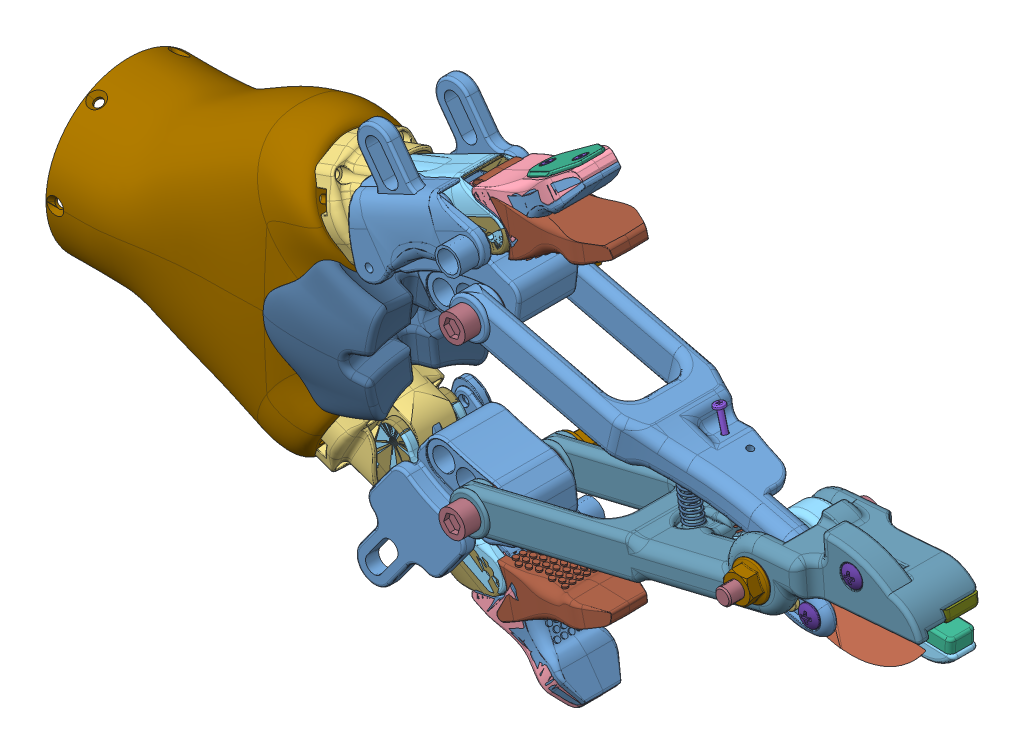
SolidWorks assembly Assiem_Gripper_Utensile, configuration Default. Lengths in mm.
Overall size (320.66 194.91 65.01).
98 component instances, 35 part files, 61 mates.
Components (placement in the parent):
- Assieme_Case_sx-1: Assieme_Case_sx [Default] at origin size (167.73 210 74) (hidden)
  - Case_sx_v5-1: Case_sx_v5 [Default] at origin size (167.73 210 74)
  - Grano_filettato_ENT3_6-1: Grano_filettato_ENT3_6 [Default] at (62 96 31) size (5 5 6)
  - Grano_filettato_ENT3_6-20: Grano_filettato_ENT3_6 [Default] at (109.2647 71.1343 31) x (0.987351 0.158553 0) z (0 0 1) size (5 5 6)
  - Grano_filettato_ENT3_6-22: Grano_filettato_ENT3_6 [Default] at (127 35 31) x (0.959125 0.282984 0) z (0 0 1) size (5 5 6)
  - Grano_filettato_ENT3_6-24: Grano_filettato_ENT3_6 [Default] at (127 -35 31) x (0.928571 0.371154 0) z (0 0 1) size (5 5 6)
  - Grano_filettato_ENT3_6-26: Grano_filettato_ENT3_6 [Default] at (109.2647 -71.1343 31) x (0.906989 0.421154 0) z (0 0 1) size (5 5 6)
  - Grano_filettato_ENT3_6-28: Grano_filettato_ENT3_6 [Default] at (62 -96 31) x (0.902849 0.429957 0) z (0 0 1) size (5 5 6)
  - Grano_filettato_ENT3_6-30: Grano_filettato_ENT3_6 [Default] at (6 8 31) x (0.823258 0.567667 0) z (0 0 1) size (5 5 6)
  - Grano_filettato_ENT3_6-32: Grano_filettato_ENT3_6 [Default] at (6 -8 31) x (0.744275 0.667874 0) z (0 0 1) size (5 5 6)
  - Grano_filettato_ENT3_6-34: Grano_filettato_ENT3_6 [Default] at (14 4 0) x (0 0.852489 -0.522745) z (1 0 0) size (5 5 6)
  - Grano_filettato_ENT3_6-36: Grano_filettato_ENT3_6 [Default] at (14 -4 0) x (0 0.932569 -0.360992) z (1 0 0) size (5 5 6)
  - Grano_MSTH6_20-1: Grano_MSTH6_20 [Default] at (0 30.95 -26.5) x (0 0 -1) z (-1 0 0) size (20 6 5.85)
  - Grano_MSTH6_20-2: Grano_MSTH6_20 [Default] at (0 -30.95 -26.5) x (0 0 -1) z (-1 0 0) size (20 6 5.85)
- Assieme_Ingresso_sup-1: Assieme_Ingresso_sup [Default] at (0 30.95 -16.0586) x (0.999806 -0.019711 0) z (0 0 1) size (56.76 55.15 35.08)
  - Ingresso_sup_f_v2-1: Ingresso_sup_f_v2 [Default] at origin size (77.62 68.68 45)
  - BOCCOLA_RSONLINE-1: BOCCOLA_RSONLINE [Default] at (37.0002 1.9973 4.0586) x (0 0 1) z (-0.862361 0.506294 0) size (4 12 12)
  - BOCCOLA_RSONLINE-2: BOCCOLA_RSONLINE [Default] at (37.0002 1.9973 28.0586) x (0 0 -1) z (0.381483 -0.924376 0) size (4 12 12)
- Assieme_case_dx-1: Assieme_case_dx [Default] at (0 0 34) size (145 210 23.5) (hidden)
  - Case_dx_v5-1: Case_dx_v5 [Default] at origin size (145 210 16)
  - Grano_MSTH6_20-1: Grano_MSTH6_20 [Default] at (0 30.95 -7.5) x (0 0 1) z (-1 0 0) size (20 6 5.85)
  - Grano_MSTH6_20-2: Grano_MSTH6_20 [Default] at (0 -30.95 -7.5) x (0 0 1) z (-1 0 0) size (20 6 5.85)
- KG-2-1: KG-2 [Default] at (-119.5648 0 0) x (-1 0 0) z (0 -1 0) size (190.12 63.02 189.85)
  - KG-2.STEP-1: KG-2.STEP [Default] at origin size (198.06 63.02 194.91)
    - AM 3540 0001 - Linear Actuator - 35mm - 40N - Dummy simple.STEP-1: AM 3540 0001 - Linear Actuator - 35mm - 40N - Dummy simple.STEP [Default] at (-86.7275 0 30.1692) x (-0.939693 0 0.34202) z (0 1 0) size (59.16 39 39) (hidden)
      - DummyActuator_D_faut.STEP-1: DummyActuator_D_faut.STEP [Default] at origin size (44.13 37 37)
      - MF3915 0001 - Mico finger actuator plastic cup for junction with hand_D_faut.STEP-1: MF3915 0001 - Mico finger actuator plastic cup for junction with hand_D_faut.STEP [Default] at (-13 0 0) x (-1 0 0) z (0 0 -1) size (15.02 39 39)
    - AM 3540 0001 - Linear Actuator - 35mm - 40N - Dummy simple.STEP-2: AM 3540 0001 - Linear Actuator - 35mm - 40N - Dummy simple.STEP [Default] at (-86.7275 0 -30.1692) x (-0.939693 0 -0.34202) z (0 -1 0) size (59.16 39 39) (hidden)
      - DummyActuator_D_faut.STEP-1: DummyActuator_D_faut.STEP [Default] at origin size (44.13 37 37)
      - MF3915 0001 - Mico finger actuator plastic cup for junction with hand_D_faut.STEP-1: MF3915 0001 - Mico finger actuator plastic cup for junction with hand_D_faut.STEP [Default] at (-13 0 0) x (-1 0 0) z (0 0 -1) size (15.02 39 39)
    - AM 3240 0004 - Plastic Finger Assembly Mico - 32mm - 2 Phalanges_simple_D_faut.STEP-1: AM 3240 0004 - Plastic Finger Assembly Mico - 32mm - 2 Phalanges_simple_D_faut.STEP [Default] at (-93.8204 0 -32.7508) x (-0.34202 0 0.939693) z (0.939693 0 0.34202) size (47.27 36.79 116.14)
      - MI 0000 0001 - 1.0.0.0011_simple_D_faut.STEP-1: MI 0000 0001 - 1.0.0.0011_simple_D_faut.STEP [Default] at (0 0 -13.5762) x (0 0 1) z (0 1 0) size (36.76 36.64 36.79)
      - MI 0000 0002 - 1.0.0.0005_simple_molded_version.STEP-1: MI 0000 0002 - 1.0.0.0005_simple_molded_version.STEP [Default] at (-0.0949 0 -66.3867) x (-0.34202 0 -0.939693) z (0 -1 0) size (53.08 21.63 24.15)
      - MI 0000 0004 - 1.0.0.0005_simple_D_faut.STEP-1: MI 0000 0004 - 1.0.0.0005_simple_D_faut.STEP [Default] at (5.2287 0 -24.6775) x (-0.173648 0 -0.984808) z (0 -1 0) size (57.72 28.12 23.54)
      - MI 1502 0001 - 1.0.0.0002_simple_D_faut.STEP-1: MI 1502 0001 - 1.0.0.0002_simple_D_faut.STEP [Default] at (-16.391 0 -80.0717) x (0 1 0) z (-0.97437 0 0.224951) size (19.37 25 1.26)
      - MH 0205 0003 - M2x5 washer, stainless, black oxyde, 0.3 thick_simple_D_faut.STEP-1: MH 0205 0003 - M2x5 washer, stainless, black oxyde, 0.3 thick_simple_D_faut.STEP [Default] at (-18.5389 0 -84.7073) x (-0.224951 0.000713 -0.97437) z (0.97437 0 -0.224951) size (5 5 0.3)
      - MH 0205 0003 - M2x5 washer, stainless, black oxyde, 0.3 thick_simple_D_faut.STEP-2: MH 0205 0003 - M2x5 washer, stainless, black oxyde, 0.3 thick_simple_D_faut.STEP [Default] at (-21.9132 0 -99.3229) x (-0.224951 0.000713 -0.97437) z (0.97437 0 -0.224951) size (5 5 0.3)
      - MH 0204 0004 - Lamix M2x4 stainless steel screw, head 0.3 thick,  black colored_simple_D_faut.STEP-1: MH 0204 0004 - Lamix M2x4 stainless steel screw, head 0.3 thick,  black colored_simple_D_faut.STEP [Default] at (-14.6414 0 -85.6071) x (-0.028802 0.991769 -0.124755) z (0.2231 0.128036 0.96635) size (4 4.3 4)
      - MH 0204 0004 - Lamix M2x4 stainless steel screw, head 0.3 thick,  black colored_simple_D_faut.STEP-2: MH 0204 0004 - Lamix M2x4 stainless steel screw, head 0.3 thick,  black colored_simple_D_faut.STEP [Default] at (-18.0157 0 -100.2227) x (0.215322 0.289446 0.932661) z (0.065111 -0.957194 0.282028) size (4 4.3 4)
      - MH 0204 0004 - Lamix M2x4 stainless steel screw, head 0.3 thick,  black colored_simple_D_faut.STEP-3: MH 0204 0004 - Lamix M2x4 stainless steel screw, head 0.3 thick,  black colored_simple_D_faut.STEP [Default] at (-0.0949 -7.35 -66.3867) x (-0.96685 0 -0.255343) z (-0.255343 0 0.96685) size (4 4.3 4) (hidden)
      - MH 0204 0004 - Lamix M2x4 stainless steel screw, head 0.3 thick,  black colored_simple_D_faut.STEP-4: MH 0204 0004 - Lamix M2x4 stainless steel screw, head 0.3 thick,  black colored_simple_D_faut.STEP [Default] at (10.5 -7.35 -23.5762) x (-0.96685 0 -0.255343) z (-0.255343 0 0.96685) size (4 4.3 4) (hidden)
      - MH 0204 0004 - Lamix M2x4 stainless steel screw, head 0.3 thick,  black colored_simple_D_faut.STEP-5: MH 0204 0004 - Lamix M2x4 stainless steel screw, head 0.3 thick,  black colored_simple_D_faut.STEP [Default] at (-0.0949 7.35 -66.3867) size (4 4.3 4) (hidden)
      - MH 0204 0004 - Lamix M2x4 stainless steel screw, head 0.3 thick,  black colored_simple_D_faut.STEP-6: MH 0204 0004 - Lamix M2x4 stainless steel screw, head 0.3 thick,  black colored_simple_D_faut.STEP [Default] at (10.5 7.35 -23.5762) size (4 4.3 4) (hidden)
    - AM 3240 0004 - Plastic Finger Assembly Mico - 32mm - 2 Phalanges_simple_D_faut.STEP-2: AM 3240 0004 - Plastic Finger Assembly Mico - 32mm - 2 Phalanges_simple_D_faut.STEP [Default] at (-93.8204 0 32.7508) x (-0.34202 0 -0.939693) z (0.939693 0 -0.34202) size (47.27 36.79 116.14)
      - MI 0000 0001 - 1.0.0.0011_simple_D_faut.STEP-1: MI 0000 0001 - 1.0.0.0011_simple_D_faut.STEP [Default] at (0 0 -13.5762) x (0 0 1) z (0 1 0) size (36.76 36.64 36.79)
      - MI 0000 0002 - 1.0.0.0005_simple_molded_version.STEP-1: MI 0000 0002 - 1.0.0.0005_simple_molded_version.STEP [Default] at (-0.0949 0 -66.3867) x (-0.34202 0 -0.939693) z (0 -1 0) size (53.08 21.63 24.15)
      - MI 0000 0004 - 1.0.0.0005_simple_D_faut.STEP-1: MI 0000 0004 - 1.0.0.0005_simple_D_faut.STEP [Default] at (5.2287 0 -24.6775) x (-0.173648 0 -0.984808) z (0 -1 0) size (57.72 28.12 23.54)
      - MI 1502 0001 - 1.0.0.0002_simple_D_faut.STEP-1: MI 1502 0001 - 1.0.0.0002_simple_D_faut.STEP [Default] at (-16.391 0 -80.0717) x (0 1 0) z (-0.97437 0 0.224951) size (19.37 25 1.26)
      - MH 0205 0003 - M2x5 washer, stainless, black oxyde, 0.3 thick_simple_D_faut.STEP-1: MH 0205 0003 - M2x5 washer, stainless, black oxyde, 0.3 thick_simple_D_faut.STEP [Default] at (-18.5389 0 -84.7073) x (-0.224951 0.000713 -0.97437) z (0.97437 0 -0.224951) size (5 5 0.3)
      - MH 0205 0003 - M2x5 washer, stainless, black oxyde, 0.3 thick_simple_D_faut.STEP-2: MH 0205 0003 - M2x5 washer, stainless, black oxyde, 0.3 thick_simple_D_faut.STEP [Default] at (-21.9132 0 -99.3229) x (-0.224951 0.000713 -0.97437) z (0.97437 0 -0.224951) size (5 5 0.3)
      - MH 0204 0004 - Lamix M2x4 stainless steel screw, head 0.3 thick,  black colored_simple_D_faut.STEP-1: MH 0204 0004 - Lamix M2x4 stainless steel screw, head 0.3 thick,  black colored_simple_D_faut.STEP [Default] at (-14.6414 0 -85.6071) x (-0.028802 0.991769 -0.124755) z (0.2231 0.128036 0.96635) size (4 4.3 4)
      - MH 0204 0004 - Lamix M2x4 stainless steel screw, head 0.3 thick,  black colored_simple_D_faut.STEP-2: MH 0204 0004 - Lamix M2x4 stainless steel screw, head 0.3 thick,  black colored_simple_D_faut.STEP [Default] at (-18.0157 0 -100.2227) x (0.215322 0.289446 0.932661) z (0.065111 -0.957194 0.282028) size (4 4.3 4)
      - MH 0204 0004 - Lamix M2x4 stainless steel screw, head 0.3 thick,  black colored_simple_D_faut.STEP-3: MH 0204 0004 - Lamix M2x4 stainless steel screw, head 0.3 thick,  black colored_simple_D_faut.STEP [Default] at (-0.0949 -7.35 -66.3867) x (-0.96685 0 -0.255343) z (-0.255343 0 0.96685) size (4 4.3 4) (hidden)
      - MH 0204 0004 - Lamix M2x4 stainless steel screw, head 0.3 thick,  black colored_simple_D_faut.STEP-4: MH 0204 0004 - Lamix M2x4 stainless steel screw, head 0.3 thick,  black colored_simple_D_faut.STEP [Default] at (10.5 -7.35 -23.5762) x (-0.96685 0 -0.255343) z (-0.255343 0 0.96685) size (4 4.3 4) (hidden)
      - MH 0204 0004 - Lamix M2x4 stainless steel screw, head 0.3 thick,  black colored_simple_D_faut.STEP-5: MH 0204 0004 - Lamix M2x4 stainless steel screw, head 0.3 thick,  black colored_simple_D_faut.STEP [Default] at (-0.0949 7.35 -66.3867) size (4 4.3 4) (hidden)
      - MH 0204 0004 - Lamix M2x4 stainless steel screw, head 0.3 thick,  black colored_simple_D_faut.STEP-6: MH 0204 0004 - Lamix M2x4 stainless steel screw, head 0.3 thick,  black colored_simple_D_faut.STEP [Default] at (10.5 7.35 -23.5762) size (4 4.3 4) (hidden)
    - MT0062 0002 - Hand Shell Mico_D_faut.STEP-1: MT0062 0002 - Hand Shell Mico_D_faut.STEP [Default] at origin size (108.05 63.02 113.68)
    - MO 0000 0009 - rubber part handfront_D_faut.STEP-1: MO 0000 0009 - rubber part handfront_D_faut.STEP [Default] at (-21.4262 -5.1521 0) size (50.65 54.11 65.34)
- Assieme_Ingresso_sup-2: Assieme_Ingresso_sup [Default] at (0 -30.95 16.0586) x (0.999806 0.019711 0) z (0 0 -1) size (56.76 55.15 35.08)
  - Ingresso_sup_f_v2-1: Ingresso_sup_f_v2 [Default] at origin size (77.62 68.68 45)
  - BOCCOLA_RSONLINE-1: BOCCOLA_RSONLINE [Default] at (37.0002 1.9973 4.0586) x (0 0 1) z (-0.862361 0.506294 0) size (4 12 12)
  - BOCCOLA_RSONLINE-2: BOCCOLA_RSONLINE [Default] at (37.0002 1.9973 28.0586) x (0 0 -1) z (0.381483 -0.924376 0) size (4 12 12)
- FALANGETTA-1: FALANGETTA [Default] at (37.0133 54.9289 0) x (0.9838 0.179268 0) z (0 0 -1) size (53.08 21.63 24.15)
- Falange-1: Falange [Default] at (-0.6773 36.2898 0) x (0.874281 0.48542 0) z (0 0 -1) size (57.72 28.12 23.54)
- Albero_scanal_6mm-2: Albero_scanal_6mm [Default] at (144.9873 0 30.2) x (-0.467784 -0.883843 0) z (0 0 1) size (10 10 56)
- Assieme_TELAIO_COMPR-TRAZ-1: Assieme_TELAIO_COMPR-TRAZ [Default] at (-27.313 16.6114 -30.194) x (0.996829 0.079574 0) z (0 0 1) size (175.42 51.93 39.5)
  - TELAIO_COMPR-TRAZ-1: TELAIO_COMPR-TRAZ [Default] at (170.4321 -30.2694 11.694) size (175.42 51.93 39.5)
  - BATTENTE-1: BATTENTE [Default] at (278.1489 -5.0569 35.794) x (1 0 0) z (0 0 -1) size (29.64 18.26 6.08)
  - materiale_SOFT2-1: materiale_SOFT2 [Default] at (178.4321 -31.2694 31.694) x (-1 0 0) z (0 0 -1) size (38 5 13)
  - BOCCOLA_RSONLINE-1: BOCCOLA_RSONLINE [Default] at (170.4321 -30.2694 11.194) x (0 0 1) z (0.389783 0.920907 0) size (4 12 12)
  - BOCCOLA_RSONLINE-2: BOCCOLA_RSONLINE [Default] at (170.4321 -30.2694 49.694) x (0 0 -1) z (0.983445 0.181207 0) size (4 12 12)
  - pan head cross recess screw-2: pan head cross recess screw [ISO 7045 - M4 x 8 - Z - 8N] at (203.0321 -18.9694 44.794) x (0 0 -1) z (0.991033 0.133621 0) size (11.02 8 8)
  - hex thin nut chamfered gradeab_isEDEEEEo-1: hex thin nut chamfered gradeab_isEDEEEEo [ISO - 4035 - M4 - N] at (203.0321 -18.9694 34.794) x (0.5 -0.866025 0) z (0 0 1) size (7 8.08 2.2)
- Assieme_PORTALAMA_COMPR-TRAZ-1: Assieme_PORTALAMA_COMPR-TRAZ [Default] at (112.7156 34.929 -45.3573) x (0.996829 -0.079574 0) z (0 0 1) size (170.01 48.69 40)
  - PORTALAMA specchiato_COMPR-TRAZ-1: PORTALAMA specchiato_COMPR-TRAZ [Default] at (34.9488 -32.2503 55.8573) size (138.08 48.69 40)
  - LAMA5 NUOVA-1: LAMA5 NUOVA [Default] at (48.0839 -41.5236 50.8573) x (0.999898 0.014284 0) z (0 0 1) size (52.01 17.5 2.12)
  - hex thin nut chamfered gradeab_isEDEEEEo-4: hex thin nut chamfered gradeab_isEDEEEEo [ISO - 4035 - M4 - N] at (48.0839 -41.5236 49.8573) x (0.999492 -0.031877 0) z (0 0 1) size (7 8.08 2.2)
  - BOCCOLA_RSONLINE-1: BOCCOLA_RSONLINE [Default] at (34.9488 -32.2503 56.3573) x (0 0 -1) z (-0.166528 -0.986037 0) size (4 12 12)
  - BOCCOLA_RSONLINE-2: BOCCOLA_RSONLINE [Default] at (34.9488 -32.2503 45.3573) x (0 0 1) z (0.391952 0.919986 0) size (4 12 12)
  - hex thin nut chamfered gradeab_isEDEEEEo-7: hex thin nut chamfered gradeab_isEDEEEEo [ISO - 4035 - M2 - N] at (-0.2058 -19.6931 40.3573) x (0.943396 0.331667 0) z (-0.331667 0.943396 0) size (4 4.62 1.2)
  - pan head cross recess screw-4: pan head cross recess screw [ISO 7045 - M4 x 8 - Z - 8N] at (48.0839 -41.5232 57.1573) x (0 0 -1) z (0.974254 0.225454 0) size (11.02 8 8)
  - pan head cross recess screw_iso-1: pan head cross recess screw_iso [ISO 7045 - M3 x 10 - Z - 10N] at (40.0839 -41.6379 56.4573) x (0 0 -1) z (0.99999 0.004568 0) size (9.35 5.6 5.6)
  - hex thin nut chamfered gradeab_iso-1: hex thin nut chamfered gradeab_iso [ISO - 4035 - M3 - N] at (40.0839 -41.6379 49.8573) x (0.820804 0.571211 0) z (0 0 1) size (5.5 6.35 1.8)
- Assieme_ELEMETO_PRESA_COMPR-1: Assieme_ELEMETO_PRESA_COMPR [Default] at (103.6603 -2.7295 -90.8026) x (0.999391 -0.034899 0) z (0 0 1) size (87.1 36.05 10.65)
  - ELEMENTO_PRESA_COMPR-1: ELEMENTO_PRESA_COMPR [Default] at (41.2066 4.1701 73.8026) size (87.1 36.05 10.29)
  - MATERIALE_SOFT_3D-2: MATERIALE_SOFT_3D [Default] at (59.2066 4.1701 80.8026) size (38 5 10)
  - BOCCOLA_RSONLINE-1: BOCCOLA_RSONLINE [Default] at (41.2066 4.1701 80.3026) x (0 0 1) z (-0.001838 -0.999998 0) size (4 12 12)
- Battente Molla 3D-1: Battente Molla 3D [Default] at (111.3267 13.8645 -5) x (0.255546 -0.966797 0) z (-0.32048 -0.08471 0.94346) size (7 7 7)
- VITE M2x16-1: VITE M2x16 [Default] at (108.0046 26.4329 -5) x (0.740269 0.195669 0.643207) z (0.255546 -0.966797 0) size (4.1 4.1 17.2)
- Albero_scanal_6mm-3: Albero_scanal_6mm [Default] at (37.0324 32.2176 -29.2) x (0.975688 0.219162 0) z (0 0 -1) size (10 10 56)
- Albero_scanal_6mm-4: Albero_scanal_6mm [Default] at (37.0324 -32.2176 -29.2) x (0.975688 0.219162 0) z (0 0 -1) size (10 10 56)
- hex flange nut gradea_iso-1: hex flange nut gradea_iso [ISO - 4161 - M6 - N] at (144.9873 0 25.5) x (0.821214 -0.57062 0) z (0 0 1) size (14.2 14.2 6)
- hex flange nut gradea_iso-2: hex flange nut gradea_iso [ISO - 4161 - M6 - N] at (37.0324 32.2176 -26) x (0.677424 -0.735593 0) z (0 0 -1) size (14.2 14.2 6)
- hex flange nut gradea_iso-3: hex flange nut gradea_iso [ISO - 4161 - M6 - N] at (37.0324 -32.2176 -25.5) x (0.677424 -0.735593 0) z (0 0 -1) size (14.2 14.2 6)
- Molla compressione GRANDE-1: Molla compressione GRANDE [Default] at (140.0924 -5.2274 15.4108) x (-0.899578 -0.217034 -0.379019) z (0.368447 0.088892 -0.925389) size (12.74 29.79 7.06)
- Molla compressione PICCOLA-1: Molla compressione PICCOLA [Default] at (144.4092 -0.4045 2.6482) x (-0.835365 -0.482298 -0.263731) z (0.228398 0.131866 -0.964596) size (10.3 25.83 4.74)
- FALANGETTA-2: FALANGETTA [Default] at (35.2142 -57.5002 0) x (0.970485 0.241163 0) z (0 0 1) size (53.08 21.63 24.15)
- Falange-2: Falange [Default] at (-1.0555 -36.228 0) x (0.837548 -0.546364 0) z (0 0 1) size (57.72 28.12 23.54)
Mates (geometry in assembly coordinates):
- Concentrico9: concentric anti-aligned: cylinder of Assieme_Case_sx-1/Grano_MSTH6_20-1 through (0 30.95 -36.5) axis (0 0 -1) radius 3; cylinder of Assieme_Ingresso_sup-1/Boccola_JZF6_8-13 through (0 30.95 -17) axis (0 0 1) radius 3
- Coincidente11: coincident anti-aligned: plane of Assieme_Case_sx-1/Case_sx_v5-1 through (137.001 24 -26) normal (0 0 1); plane of Assieme_Ingresso_sup-1/Boccola_JZF6_8-13 through (-3.3301 35.9411 -26) normal (0 0 -1)
- Coincidente18: coincident anti-aligned: plane of Assieme_Case_sx-1/Case_sx_v5-1 through (137 20 29) normal (0 0 1); plane of Assieme_case_dx-1/Case_dx_v5-1 through (0 0 29) normal (0 0 -1)
- Coincidente19: coincident anti-aligned: plane of Assieme_Case_sx-1/Case_sx_v5-1 through (97 102 34) normal (0 1 0); plane of Assieme_case_dx-1/Case_dx_v5-1 through (95.4723 102 29) normal (0 -1 0)
- Coincidente20: coincident anti-aligned: plane of Assieme_Case_sx-1/Case_sx_v5-1 through (134 20 34) normal (1 0 0); plane of Assieme_case_dx-1/Case_dx_v5-1 through (134 -49.0244 29) normal (-1 0 0)
- Coincidente23: coincident anti-aligned: plane of Assieme_Case_sx-1 through (0 0 0) normal (0 1 0); plane of KG-2-1 through (-119.5648 0 0) normal (0 -1 0)
- Coincidente24: coincident anti-aligned: plane of Assieme_Case_sx-1 through (0 0 0) normal (0 0 1); plane of KG-2-1 through (-119.5648 0 0) normal (0 0 -1)
- Coincidente25: coincident anti-aligned: plane of Assieme_Case_sx-1/Case_sx_v5-1 through (-9.1386 -0.0001 -0.0632) normal (-1 0 0); plane of KG-2-1/KG-2.STEP-1/MO 0000 0009 - rubber part handfront_D_faut.STEP-1 through (-9.1386 0 0.0894) normal (1 0 0)
- Concentrico10: concentric anti-aligned: cylinder of Assieme_Case_sx-1/Grano_MSTH6_20-2 through (0 -30.95 -36.5) axis (0 0 -1) radius 3; cylinder of Assieme_Ingresso_sup-2/Boccola_JZF6_8-12 through (0 -30.95 -17) axis (0 0 1) radius 3
- Coincidente26: coincident anti-aligned: plane of Assieme_Case_sx-1/Case_sx_v5-1 through (137.001 -24 -26) normal (0 0 1); plane of Assieme_Ingresso_sup-2/Boccola_JZF6_8-12 through (-0.2031 -36.9466 -26) normal (0 0 -1)
- Concentrico11: concentric anti-aligned: cylinder of Assieme_Case_sx-1/Grano_MSTH6_20-1 through (0 30.95 -26.9) axis (0 0 -1) radius 1.621; cylinder of Assieme_Ingresso_sup-1/Ingresso_sup_f_v2-1 through (0 30.95 15.5) axis (0 0 1) radius 2
- Coincidente27: coincident aligned: plane of Assieme_Ingresso_sup-1/Ingresso_sup_f_v2-1 through (0 30.95 0) normal (0 0 1)
- Concentrico12: concentric aligned: cylinder of Assieme_Case_sx-1/Grano_MSTH6_20-2 through (0 -30.95 -26.9) axis (0 0 -1) radius 1.621; cylinder of Assieme_Ingresso_sup-2/Ingresso_sup_f_v2-1 through (0 -30.95 -15.5) axis (0 0 -1) radius 2
- Coincidente28: coincident anti-aligned: plane of Assieme_Ingresso_sup-2/Ingresso_sup_f_v2-1 through (0 -30.95 0) normal (0 0 -1)
- Concentrico14: concentric aligned: cylinder of KG-2-1/KG-2.STEP-1/AM 3240 0004 - Plastic Finger Assembly Mico - 32mm - 2 Phalanges_simple_D_faut.STEP-1/MI 0000 0001 - 1.0.0.0011_simple_D_faut.STEP-1 through (0.0012 30.9476 18.9153) axis (0 0 -1) radius 1.5; cylinder of Falange-1 through (0.0012 30.9476 12.1965) axis (0 0 -1) radius 1.5
- Distanza1: distance = 0.25 mm anti-aligned: plane of KG-2-1/KG-2.STEP-1/AM 3240 0004 - Plastic Finger Assembly Mico - 32mm - 2 Phalanges_simple_D_faut.STEP-1/MI 0000 0001 - 1.0.0.0011_simple_D_faut.STEP-1 through (4.3068 27.4901 7.5) normal (0 0 1); plane of Falange-1 through (35.6626 46.8553 7.75) normal (0 0 -1)
- Concentrico15: concentric aligned: cylinder of FALANGETTA-1 through (37.0133 54.9289 13.1309) axis (0 0 -1) radius 1.5; cylinder of Falange-1 through (37.0133 54.9289 12.1965) axis (0 0 -1) radius 1.5
- Distanza2: distance = 0.25 mm anti-aligned: plane of FALANGETTA-1 through (38.2926 56.4447 7.5) normal (0 0 1); plane of Falange-1 through (35.6626 46.8553 7.75) normal (0 0 -1)
- Parallelo1: parallel: line of Assieme_Ingresso_sup-1/Ingresso_sup_f_v2-1 through (21.9192 56.9589 17.5) axis (-0.884919 -0.465746 0); line of Falange-1 through (19.253 64.7419 5.75) axis (0.893474 0.449114 0)
- Concentrico17: concentric anti-aligned: circle of KG-2-1/KG-2.STEP-1/AM 3240 0004 - Plastic Finger Assembly Mico - 32mm - 2 Phalanges_simple_D_faut.STEP-1/MH 0204 0004 - Lamix M2x4 stainless steel screw, head 0.3 thick,  black colored_simple_D_faut.STEP-5; cylinder of Falange-1 through (36.6063 55.5456 12.1965) axis (0 0 -1) radius 1.5
- Concentrico20: concentric aligned: cylinder of Assieme_Ingresso_sup-1/Ingresso_sup_f_v2-1 through (36.6063 55.5456 27.5) axis (0 0 -1) radius 4; cylinder of Falange-1 through (36.6063 55.5456 12.1965) axis (0 0 -1) radius 1.5
- Concentrico21: concentric anti-aligned: cylinder of Albero_scanal_6mm-2 through (144.9873 0 -25) axis (0 0 1) radius 3; cylinder of Assieme_TELAIO_COMPR-TRAZ-1/BOCCOLA_RSONLINE-2 through (144.9873 0 19.5) axis (0 0 -1) radius 3
- Coincidente29: coincident anti-aligned: plane of Albero_scanal_6mm-2 through (144.9873 0 -19) normal (0 0 1); plane of Assieme_TELAIO_COMPR-TRAZ-1/BOCCOLA_RSONLINE-1 through (150.6814 -1.8916 -19) normal (0 0 -1)
- Concentrico22: concentric aligned: cylinder of Assieme_Ingresso_sup-2/Ingresso_sup_f_v2-1 through (36.2535 -23.2899 -17.5) axis (0 0 1) radius 4.25; cylinder of Assieme_TELAIO_COMPR-TRAZ-1/TELAIO_COMPR-TRAZ-1 through (36.2536 -23.2899 -19.5) axis (0 0 1) radius 3.2
- Coincidente30: coincident anti-aligned: plane of Assieme_Ingresso_sup-2/BOCCOLA_RSONLINE-1 through (40.1715 -37.3309 12) normal (0 0 1); plane of Assieme_TELAIO_COMPR-TRAZ-1/TELAIO_COMPR-TRAZ-1 through (37.0324 -32.2176 12) normal (0 0 -1)
- Concentrico23: concentric anti-aligned: cylinder of Albero_scanal_6mm-2 through (144.9873 0 -25) axis (0 0 1) radius 3; cylinder of Assieme_PORTALAMA_COMPR-TRAZ-1/BOCCOLA_RSONLINE-1 through (144.9873 0 11) axis (0 0 -1) radius 3
- Coincidente31: coincident anti-aligned: plane of Assieme_TELAIO_COMPR-TRAZ-1/TELAIO_COMPR-TRAZ-1 through (146.6774 -21.171 11) normal (0 0 -1); plane of Assieme_PORTALAMA_COMPR-TRAZ-1/BOCCOLA_RSONLINE-1 through (150.8053 -1.4668 11) normal (0 0 1)
- Concentrico24: concentric anti-aligned: cylinder of Assieme_Ingresso_sup-1/BOCCOLA_RSONLINE-2 through (36.2536 23.2899 12) axis (0 0 -1) radius 3; cylinder of Assieme_PORTALAMA_COMPR-TRAZ-1/PORTALAMA specchiato_COMPR-TRAZ-1 through (36.2536 23.2899 -20) axis (0 0 1) radius 3.2
- Concentrico25: concentric aligned: cylinder of Albero_scanal_6mm-2 through (144.9873 0 -25) axis (0 0 1) radius 3; cylinder of Assieme_ELEMETO_PRESA_COMPR-1/BOCCOLA_RSONLINE-1 through (144.9873 0 -10.5) axis (0 0 1) radius 3
- Coincidente32: coincident anti-aligned: plane of Assieme_TELAIO_COMPR-TRAZ-1/TELAIO_COMPR-TRAZ-1 through (146.6774 -21.171 -10.5) normal (0 0 1); plane of Assieme_ELEMETO_PRESA_COMPR-1/BOCCOLA_RSONLINE-1 through (138.9914 0.2204 -10.5) normal (0 0 -1)
- Parallelo2: parallel aligned: line of Assieme_ELEMETO_PRESA_COMPR-1/MATERIALE_SOFT_3D-2 through (163.9758 -0.6631 -1) axis (0.999391 -0.034899 0)
- Coincidente36: coincident anti-aligned: line of Albero_scanal_6mm-2 through (144.9873 0 31) axis (-1 0 0)
- Concentrico26: concentric anti-aligned: cylinder of Assieme_PORTALAMA_COMPR-TRAZ-1/PORTALAMA specchiato_COMPR-TRAZ-1 through (108.7712 23.5325 -5) axis (0.255546 -0.966797 0) radius 1.25; cylinder of Battente Molla 3D-1 through (109.9734 18.9843 -5) axis (-0.255546 0.966797 0) radius 1.2
- Coincidente37: coincident anti-aligned: plane of Assieme_PORTALAMA_COMPR-TRAZ-1/PORTALAMA specchiato_COMPR-TRAZ-1 through (114.2093 14.6264 -0.5) normal (0.255546 -0.966797 0); plane of Battente Molla 3D-1 through (112.4213 14.1538 -4.6022) normal (-0.255546 0.966797 0)
- Parallelo3: parallel: plane of Assieme_TELAIO_COMPR-TRAZ-1/BATTENTE-1; line of Assieme_PORTALAMA_COMPR-TRAZ-1/LAMA5 NUOVA-1 through (163.5745 0.0206 5.5067) axis (0.999998 0.002133 0)
- Concentrico27: concentric anti-aligned: cylinder of Assieme_PORTALAMA_COMPR-TRAZ-1/PORTALAMA specchiato_COMPR-TRAZ-1 through (108.7712 23.5325 -5) axis (0.255546 -0.966797 0) radius 1.25; cylinder of VITE M2x16-1 through (112.0933 10.9641 -5) axis (-0.255546 0.966797 0) radius 1
- Distanza3: distance = 8 mm anti-aligned: plane of VITE M2x16-1 through (108.0046 26.4329 -5) normal (0.255546 -0.966797 0); plane of Assieme_PORTALAMA_COMPR-TRAZ-1/PORTALAMA specchiato_COMPR-TRAZ-1 through (114.1534 19.7834 -0.5) normal (-0.255546 0.966797 0)
- Concentrico28: concentric aligned: cylinder of Assieme_Ingresso_sup-1/Ingresso_sup_f_v2-1 through (13.4276 16.6077 -3.8492) axis (0 0 1) radius 4.25; cylinder of Assieme_PORTALAMA_COMPR-TRAZ-1/PORTALAMA specchiato_COMPR-TRAZ-1 through (13.4276 16.6077 -20) axis (0 0 1) radius 3.2
- Concentrico29: concentric anti-aligned: cylinder of Assieme_Ingresso_sup-2/Ingresso_sup_f_v2-1 through (18.9827 -25.8849 3.8492) axis (0 0 -1) radius 4.25; cylinder of Assieme_TELAIO_COMPR-TRAZ-1/TELAIO_COMPR-TRAZ-1 through (18.9827 -25.8849 -19.5) axis (0 0 1) radius 3.2
- Portalama FORO 1: concentric anti-aligned: cylinder of Assieme_Ingresso_sup-1/Ingresso_sup_f_v2-1 through (17.5727 23.1257 17.5) axis (0 0 -1) radius 4.25; cylinder of Assieme_PORTALAMA_COMPR-TRAZ-1/PORTALAMA specchiato_COMPR-TRAZ-1 through (36.2536 23.2899 -20) axis (0 0 1) radius 3.2
- Telaio FORO 1: concentric aligned: cylinder of Assieme_Ingresso_sup-2/Ingresso_sup_f_v2-1 through (17.5727 -23.1257 -17.5) axis (0 0 1) radius 4.25; cylinder of Assieme_TELAIO_COMPR-TRAZ-1/TELAIO_COMPR-TRAZ-1 through (36.2536 -23.2899 -19.5) axis (0 0 1) radius 3.2
- Portalama FORO 2: concentric anti-aligned: cylinder of Assieme_Ingresso_sup-1/Ingresso_sup_f_v2-1 through (26.9461 23.7167 17.5) axis (0 0 -1) radius 4.25; cylinder of Assieme_PORTALAMA_COMPR-TRAZ-1/PORTALAMA specchiato_COMPR-TRAZ-1 through (36.2536 23.2899 -20) axis (0 0 1) radius 3.2
- Telaio FORO 2: concentric aligned: cylinder of Assieme_Ingresso_sup-2/Ingresso_sup_f_v2-1 through (26.9461 -23.7167 -17.5) axis (0 0 1) radius 4.25; cylinder of Assieme_TELAIO_COMPR-TRAZ-1/TELAIO_COMPR-TRAZ-1 through (36.2536 -23.2899 -19.5) axis (0 0 1) radius 3.2
- Portalama FORO 3: concentric anti-aligned: cylinder of Assieme_Ingresso_sup-1/BOCCOLA_RSONLINE-2 through (37.0324 32.2176 12) axis (0 0 -1) radius 3; cylinder of Assieme_PORTALAMA_COMPR-TRAZ-1/PORTALAMA specchiato_COMPR-TRAZ-1 through (37.0324 32.2176 -20) axis (0 0 1) radius 3.2
- Telaio FORO3: concentric anti-aligned: cylinder of Assieme_Ingresso_sup-2/BOCCOLA_RSONLINE-1 through (37.0324 -32.2176 12) axis (0 0 -1) radius 3; cylinder of Assieme_TELAIO_COMPR-TRAZ-1/TELAIO_COMPR-TRAZ-1 through (37.0324 -32.2176 -19.5) axis (0 0 1) radius 3.2
- Concentrico30: concentric anti-aligned: cylinder of Assieme_PORTALAMA_COMPR-TRAZ-1/PORTALAMA specchiato_COMPR-TRAZ-1 through (37.0324 32.2176 -20) axis (0 0 1) radius 3.2; cylinder of Albero_scanal_6mm-3 through (37.0324 32.2176 26) axis (0 0 -1) radius 3
- Coincidente38: coincident anti-aligned: plane of Assieme_PORTALAMA_COMPR-TRAZ-1/PORTALAMA specchiato_COMPR-TRAZ-1 through (37.0324 32.2176 20) normal (0 0 1); plane of Albero_scanal_6mm-3 through (37.0324 32.2176 20) normal (0 0 -1)
- Concentrico31: concentric anti-aligned: cylinder of Assieme_TELAIO_COMPR-TRAZ-1/TELAIO_COMPR-TRAZ-1 through (37.0324 -32.2176 -19.5) axis (0 0 1) radius 3.2; cylinder of Albero_scanal_6mm-4 through (37.0324 -32.2176 26) axis (0 0 -1) radius 3
- Coincidente39: coincident anti-aligned: plane of Assieme_TELAIO_COMPR-TRAZ-1/TELAIO_COMPR-TRAZ-1 through (37.0324 -32.2176 20) normal (0 0 1); plane of Albero_scanal_6mm-4 through (37.0324 -32.2176 20) normal (0 0 -1)
- Concentrico32: concentric aligned: cylinder of Albero_scanal_6mm-2 through (144.9873 0 -25) axis (0 0 1) radius 3; cylinder of hex flange nut gradea_iso-1 through (144.9873 0 19.5) axis (0 0 1) radius 2.5
- Coincidente41: coincident anti-aligned: plane of Assieme_TELAIO_COMPR-TRAZ-1/BOCCOLA_RSONLINE-2 through (143.434 5.7954 19.5) normal (0 0 1); plane of hex flange nut gradea_iso-1 through (148.2818 4.7413 19.5) normal (0 0 -1)
- Concentrico33: concentric aligned: cylinder of Albero_scanal_6mm-3 through (37.0324 32.2176 26) axis (0 0 -1) radius 3; cylinder of hex flange nut gradea_iso-2 through (37.0324 32.2176 -20) axis (0 0 -1) radius 2.5
- Coincidente42: coincident anti-aligned: plane of Assieme_PORTALAMA_COMPR-TRAZ-1/PORTALAMA specchiato_COMPR-TRAZ-1 through (37.0324 32.2176 -20) normal (0 0 -1); plane of hex flange nut gradea_iso-2 through (32.7854 28.3065 -20) normal (0 0 1)
- Concentrico34: concentric anti-aligned: cylinder of Albero_scanal_6mm-4 through (37.0324 -32.2176 26) axis (0 0 -1) radius 3; circle of hex flange nut gradea_iso-3
- Coincidente43: coincident anti-aligned: plane of Assieme_TELAIO_COMPR-TRAZ-1/TELAIO_COMPR-TRAZ-1 through (37.0324 -32.2176 -19.5) normal (0 0 -1); plane of hex flange nut gradea_iso-3 through (32.7854 -36.1287 -19.5) normal (0 0 1)
- Concentrico35: concentric aligned: circle of Assieme_TELAIO_COMPR-TRAZ-1/TELAIO_COMPR-TRAZ-1; circle of Molla compressione GRANDE-1
- Concentrico36: concentric aligned: circle of Assieme_ELEMETO_PRESA_COMPR-1/ELEMENTO_PRESA_COMPR-1; circle of Molla compressione PICCOLA-1
- Concentrico37: concentric aligned: cylinder of FALANGETTA-2 through (35.2142 -57.5002 -13.1309) axis (0 0 1) radius 1.5; cylinder of Falange-2 through (35.2142 -57.5002 -12.1965) axis (0 0 1) radius 1.5
- Distanza4: distance = 0.25 mm anti-aligned: plane of FALANGETTA-2 through (37.0037 -58.3558 -7.5) normal (0 0 -1); plane of Falange-2 through (34.441 -49.3511 -7.75) normal (0 0 1)
- Concentrico38: concentric anti-aligned: circle of KG-2-1/KG-2.STEP-1/AM 3240 0004 - Plastic Finger Assembly Mico - 32mm - 2 Phalanges_simple_D_faut.STEP-2/MH 0204 0004 - Lamix M2x4 stainless steel screw, head 0.3 thick,  black colored_simple_D_faut.STEP-4; cylinder of Falange-2 through (0.0012 -30.9476 12.1965) axis (0 0 -1) radius 1.5
- Coincidente44: coincident aligned: plane of KG-2-1/KG-2.STEP-1/AM 3240 0004 - Plastic Finger Assembly Mico - 32mm - 2 Phalanges_simple_D_faut.STEP-2/MI 0000 0004 - 1.0.0.0005_simple_D_faut.STEP-1 through (35.9604 -56.5387 11.25) normal (0 0 1); plane of Falange-2 through (34.5152 -58.4567 11.25) normal (0 0 1)
